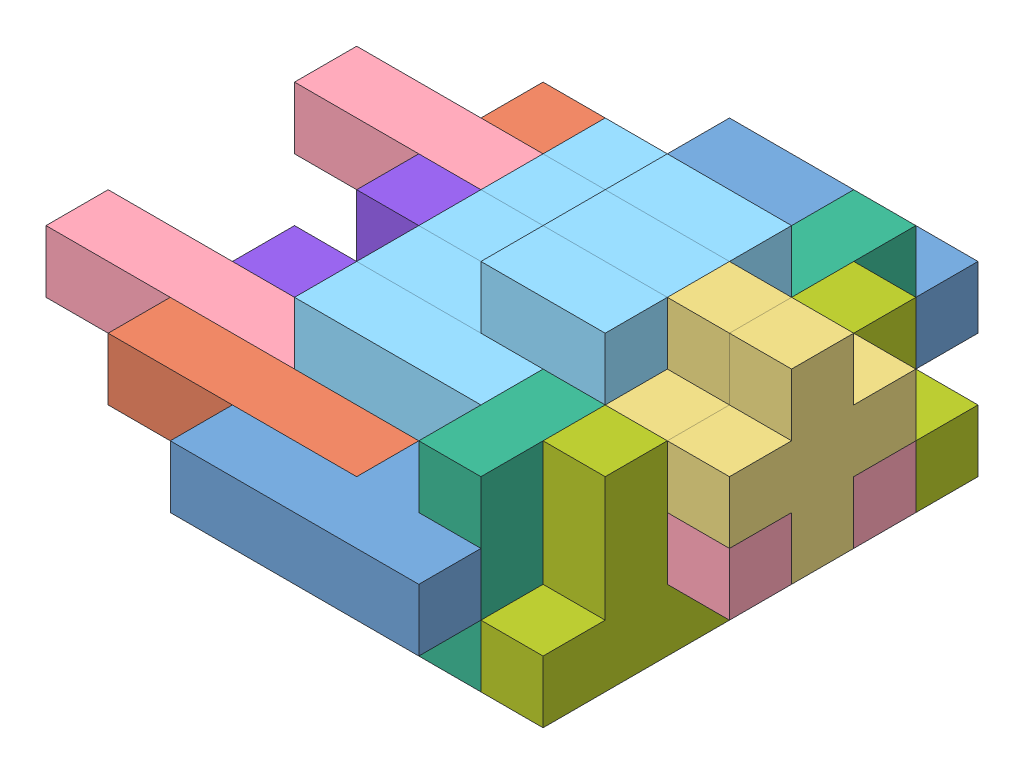
SolidWorks assembly Assem1, configuration Default. Lengths in mm.
Overall size (254 101.6 228.6).
23 component instances, 8 part files, 65 mates.
Components (placement in the parent):
- Block01-1: Block01 [Default] at (-218.9501 81.5478 299.8622) x (1 0 0) z (0 1 0) size (101.6 50.8 25.4)
- Block02-1: Block02 [Default] at (-168.1501 106.9478 274.4622) x (-1 0 0) z (0 -1 0) size (101.6 50.8 25.4)
- Block04-1: Block04 [Default] at (-117.3501 81.5478 223.6622) x (0 0 -1) z (1 0 0) size (76.2 76.2 25.4)
- Block05-1: Block05 [Default] at (-320.5501 81.5478 122.0622) size (127 25.4 25.4)
- Block06-1: Block06 [Default] at (-218.9501 81.5478 223.6622) size (101.6 50.8 25.4)
- Block07-1: Block07 [Default] at (-117.3501 132.3478 96.6622) x (0 -1 0) z (-1 0 0) size (76.2 76.2 25.4)
- Block08-1: Block08 [Default] at (-218.9501 106.9478 223.6622) x (0 0 -1) z (0 -1 0) size (76.2 76.2 25.4)
- Block11-1: Block11 [Default] at (-218.9501 106.9478 147.4622) x (0 0 1) z (0 -1 0) size (76.2 50.8 25.4)
- Block05-2: Block05 [Default] at (-320.5501 81.5478 223.6622) size (127 25.4 25.4)
- Block02-2: Block02 [Default] at (-168.1501 81.5478 96.6622) x (-1 0 0) z (0 1 0) size (101.6 50.8 25.4)
- Block01-2: Block01 [Default] at (-218.9501 106.9478 71.2622) x (1 0 0) z (0 -1 0) size (101.6 50.8 25.4)
- Block06-3: Block06 [Default] at (-218.9501 81.5478 122.0622) size (101.6 50.8 25.4)
- Block06-4: Block06 [Default] at (-218.9501 157.7478 172.8622) x (1 0 0) z (0 0 -1) size (101.6 50.8 25.4)
- Block06-5: Block06 [Default] at (-218.9501 157.7478 223.6622) x (1 0 0) z (0 0 -1) size (101.6 50.8 25.4)
- Block06-6: Block06 [Default] at (-218.9501 157.7478 198.2622) x (1 0 0) z (0 0 -1) size (101.6 50.8 25.4)
- Block07-2: Block07 [Default] at (-117.3501 132.3478 274.4622) x (0 0 -1) z (-1 0 0) size (76.2 76.2 25.4)
- Block05-3: Block05 [Default] at (-193.5501 81.5478 198.2622) size (127 25.4 25.4)
- Block05-4: Block05 [Default] at (-193.5501 81.5478 147.4622) size (127 25.4 25.4)
- Block01-3: Block01 [Default] at (-218.9501 81.5478 223.6622) x (1 0 0) z (0 -1 0) size (101.6 50.8 25.4)
- Block01-4: Block01 [Default] at (-218.9501 56.1478 147.4622) x (1 0 0) z (0 1 0) size (101.6 50.8 25.4)
- Block04-3: Block04 [Default] at (-91.9501 81.5478 223.6622) x (0 0 -1) z (1 0 0) size (76.2 76.2 25.4)
- Block08-2: Block08 [Default] at (-117.3501 56.1478 274.4622) x (0 0 -1) z (1 0 0) size (76.2 76.2 25.4)
- Block08-4: Block08 [Default] at (-117.3501 56.1478 172.8622) x (0 0 -1) z (1 0 0) size (76.2 76.2 25.4)
Mates (geometry in assembly coordinates):
- Coincident1: coincident anti-aligned: plane of Block05-1 through (-320.5501 81.5478 147.4622) normal (0 0 1); plane of Block11-1 through (-269.7501 81.5478 147.4622) normal (0 0 -1)
- Coincident4: coincident aligned: plane of Block05-1 through (-320.5501 106.9478 147.4622) normal (0 1 0); plane of Block11-1 through (-218.9501 106.9478 147.4622) normal (0 1 0)
- Coincident7: coincident aligned: plane of Block05-1 through (-193.5501 106.9478 147.4622) normal (1 0 0); plane of Block08-1 through (-193.5501 81.5478 147.4622) normal (1 0 0)
- Coincident8: coincident aligned: plane of Block05-1 through (-193.5501 81.5478 147.4622) normal (0 -1 0); plane of Block08-1 through (-218.9501 81.5478 223.6622) normal (0 -1 0)
- Coincident9: coincident anti-aligned: plane of Block05-1 through (-320.5501 81.5478 147.4622) normal (0 0 1); plane of Block08-1 through (-218.9501 81.5478 147.4622) normal (0 0 -1)
- Coincident10: coincident anti-aligned: plane of Block08-1 through (-218.9501 81.5478 223.6622) normal (-1 0 0); plane of Block11-1 through (-218.9501 81.5478 147.4622) normal (1 0 0)
- Coincident11: coincident anti-aligned: plane of Block11-1 through (-218.9501 81.5478 223.6622) normal (0 0 1); plane of Block05-2 through (-320.5501 81.5478 223.6622) normal (0 0 -1)
- Coincident12: coincident aligned: plane of Block08-1 through (-193.5501 81.5478 198.2622) normal (1 0 0); plane of Block05-2 through (-193.5501 106.9478 249.0622) normal (1 0 0)
- Coincident13: coincident aligned: plane of Block08-1 through (-218.9501 81.5478 223.6622) normal (0 -1 0); plane of Block05-2 through (-193.5501 81.5478 249.0622) normal (0 -1 0)
- Coincident14: coincident anti-aligned: plane of Block02-1 through (-269.7501 81.5478 249.0622) normal (0 0 -1); plane of Block05-2 through (-320.5501 81.5478 249.0622) normal (0 0 1)
- Coincident15: coincident aligned: plane of Block02-1 through (-168.1501 106.9478 274.4622) normal (0 1 0); plane of Block05-2 through (-320.5501 106.9478 249.0622) normal (0 1 0)
- Coincident16: coincident anti-aligned: plane of Block02-1 through (-193.5501 81.5478 249.0622) normal (-1 0 0); plane of Block08-1 through (-193.5501 81.5478 198.2622) normal (1 0 0)
- Coincident17: coincident anti-aligned: plane of Block05-1 through (-320.5501 81.5478 122.0622) normal (0 0 -1); plane of Block02-2 through (-269.7501 106.9478 122.0622) normal (0 0 1)
- Coincident18: coincident aligned: plane of Block05-1 through (-320.5501 106.9478 147.4622) normal (0 1 0); plane of Block02-2 through (-168.1501 106.9478 96.6622) normal (0 1 0)
- Coincident19: coincident anti-aligned: plane of Block05-1 through (-193.5501 106.9478 147.4622) normal (1 0 0); plane of Block02-2 through (-193.5501 106.9478 122.0622) normal (-1 0 0)
- Coincident20: coincident anti-aligned: plane of Block01-1 through (-168.1501 106.9478 274.4622) normal (0 0 -1); plane of Block02-1 through (-168.1501 81.5478 274.4622) normal (0 0 1)
- Coincident21: coincident anti-aligned: plane of Block01-1 through (-168.1501 106.9478 249.0622) normal (-1 0 0); plane of Block02-1 through (-168.1501 81.5478 223.6622) normal (1 0 0)
- Coincident22: coincident aligned: plane of Block01-1 through (-218.9501 106.9478 299.8622) normal (0 1 0); plane of Block02-1 through (-168.1501 106.9478 274.4622) normal (0 1 0)
- Coincident24: coincident anti-aligned: plane of Block02-2 through (-168.1501 106.9478 96.6622) normal (0 0 -1); plane of Block01-2 through (-168.1501 81.5478 96.6622) normal (0 0 1)
- Coincident25: coincident aligned: plane of Block02-2 through (-168.1501 106.9478 96.6622) normal (0 1 0); plane of Block01-2 through (-218.9501 106.9478 71.2622) normal (0 1 0)
- Coincident26: coincident aligned: plane of Block01-1 through (-117.3501 106.9478 299.8622) normal (1 0 0); plane of Block01-2 through (-117.3501 81.5478 71.2622) normal (1 0 0)
- Coincident27: coincident anti-aligned: plane of Block02-1 through (-168.1501 106.9478 274.4622) normal (0 1 0); plane of Block06-1 through (-218.9501 106.9478 249.0622) normal (0 -1 0)
- Coincident28: coincident aligned: plane of Block01-1 through (-117.3501 106.9478 299.8622) normal (1 0 0); plane of Block06-1 through (-117.3501 81.5478 249.0622) normal (1 0 0)
- Coincident29: coincident aligned: plane of Block06-1 through (-218.9501 81.5478 249.0622) normal (0 0 1); plane of Block05-2 through (-320.5501 81.5478 249.0622) normal (0 0 1)
- Coincident39: coincident aligned: plane of Block02-2 through (-193.5501 106.9478 147.4622) normal (0 0 1); plane of Block06-3 through (-218.9501 81.5478 147.4622) normal (0 0 1)
- Coincident40: coincident aligned: plane of Block06-1 through (-142.7501 132.3478 249.0622) normal (0 1 0); plane of Block06-3 through (-142.7501 132.3478 147.4622) normal (0 1 0)
- Coincident41: coincident aligned: plane of Block06-1 through (-218.9501 132.3478 249.0622) normal (-1 0 0); plane of Block06-3 through (-218.9501 132.3478 147.4622) normal (-1 0 0)
- Coincident42: coincident anti-aligned: plane of Block08-1 through (-218.9501 106.9478 223.6622) normal (0 1 0); plane of Block06-4 through (-142.7501 106.9478 147.4622) normal (0 -1 0)
- Coincident43: coincident aligned: plane of Block06-3 through (-218.9501 132.3478 147.4622) normal (-1 0 0); plane of Block06-4 through (-218.9501 106.9478 147.4622) normal (-1 0 0)
- Coincident44: coincident anti-aligned: plane of Block06-3 through (-218.9501 81.5478 147.4622) normal (0 0 1); plane of Block06-4 through (-218.9501 157.7478 147.4622) normal (0 0 -1)
- Coincident45: coincident aligned: plane of Block06-4 through (-168.1501 132.3478 147.4622) normal (-1 0 0); plane of Block06-5 through (-168.1501 132.3478 198.2622) normal (-1 0 0)
- Coincident46: coincident anti-aligned: plane of Block06-1 through (-218.9501 81.5478 223.6622) normal (0 0 -1); plane of Block06-5 through (-218.9501 157.7478 223.6622) normal (0 0 1)
- Coincident47: coincident aligned: plane of Block06-4 through (-168.1501 157.7478 147.4622) normal (0 1 0); plane of Block06-5 through (-168.1501 157.7478 198.2622) normal (0 1 0)
- Coincident49: coincident aligned: plane of Block06-4 through (-168.1501 157.7478 147.4622) normal (0 1 0); plane of Block06-6 through (-168.1501 157.7478 172.8622) normal (0 1 0)
- Coincident51: coincident aligned: plane of Block06-5 through (-168.1501 132.3478 198.2622) normal (-1 0 0); plane of Block06-6 through (-168.1501 132.3478 172.8622) normal (-1 0 0)
- Coincident56: coincident anti-aligned: plane of Block06-1 through (-117.3501 106.9478 249.0622) normal (0 1 0); plane of Block07-2 through (-142.7501 106.9478 198.2622) normal (0 -1 0)
- Coincident57: coincident anti-aligned: plane of Block01-1 through (-117.3501 106.9478 274.4622) normal (0 0 -1); plane of Block07-2 through (-142.7501 56.1478 274.4622) normal (0 0 1)
- Coincident58: coincident aligned: plane of Block01-1 through (-117.3501 106.9478 299.8622) normal (1 0 0); plane of Block07-2 through (-117.3501 132.3478 274.4622) normal (1 0 0)
- Coincident59: coincident aligned: plane of Block07-1 through (-117.3501 132.3478 96.6622) normal (1 0 0); plane of Block01-2 through (-117.3501 81.5478 71.2622) normal (1 0 0)
- Coincident60: coincident anti-aligned: plane of Block07-1 through (-142.7501 132.3478 96.6622) normal (0 0 -1); plane of Block01-2 through (-117.3501 81.5478 96.6622) normal (0 0 1)
- Coincident61: coincident aligned: plane of Block07-1 through (-142.7501 132.3478 172.8622) normal (0 1 0); plane of Block07-2 through (-142.7501 132.3478 274.4622) normal (0 1 0)
- Coincident62: coincident aligned: plane of Block05-2 through (-193.5501 81.5478 249.0622) normal (0 -1 0); plane of Block05-3 through (-66.5501 81.5478 223.6622) normal (0 -1 0)
- Coincident63: coincident anti-aligned: plane of Block08-1 through (-193.5501 81.5478 198.2622) normal (1 0 0); plane of Block05-3 through (-193.5501 81.5478 223.6622) normal (-1 0 0)
- Coincident64: coincident anti-aligned: plane of Block08-1 through (-142.7501 81.5478 198.2622) normal (0 0 1); plane of Block05-3 through (-193.5501 81.5478 198.2622) normal (0 0 -1)
- Coincident65: coincident aligned: plane of Block05-3 through (-66.5501 106.9478 223.6622) normal (1 0 0); plane of Block05-4 through (-66.5501 106.9478 172.8622) normal (1 0 0)
- Coincident66: coincident aligned: plane of Block02-2 through (-168.1501 81.5478 96.6622) normal (0 -1 0); plane of Block05-4 through (-66.5501 81.5478 172.8622) normal (0 -1 0)
- Coincident67: coincident anti-aligned: plane of Block08-1 through (-193.5501 81.5478 172.8622) normal (0 0 -1); plane of Block05-4 through (-193.5501 81.5478 172.8622) normal (0 0 1)
- Coincident68: coincident aligned: plane of Block07-2 through (-142.7501 56.1478 274.4622) normal (0 0 1); plane of Block01-3 through (-142.7501 56.1478 274.4622) normal (0 0 1)
- Coincident69: coincident aligned: plane of Block07-2 through (-142.7501 56.1478 249.0622) normal (0 -1 0); plane of Block01-3 through (-218.9501 56.1478 223.6622) normal (0 -1 0)
- Coincident70: coincident anti-aligned: plane of Block07-2 through (-142.7501 132.3478 274.4622) normal (-1 0 0); plane of Block01-3 through (-142.7501 56.1478 249.0622) normal (1 0 0)
- Coincident71: coincident anti-aligned: plane of Block07-1 through (-142.7501 132.3478 96.6622) normal (-1 0 0); plane of Block01-4 through (-142.7501 81.5478 122.0622) normal (1 0 0)
- Coincident72: coincident anti-aligned: plane of Block02-2 through (-168.1501 81.5478 96.6622) normal (0 -1 0); plane of Block01-4 through (-218.9501 81.5478 147.4622) normal (0 1 0)
- Coincident73: coincident anti-aligned: plane of Block07-1 through (-142.7501 56.1478 122.0622) normal (0 0 1); plane of Block01-4 through (-168.1501 81.5478 122.0622) normal (0 0 -1)
- Coincident74: coincident anti-aligned: plane of Block04-1 through (-117.3501 81.5478 223.6622) normal (-1 0 0); plane of Block07-1 through (-117.3501 132.3478 96.6622) normal (1 0 0)
- Coincident75: coincident anti-aligned: plane of Block04-1 through (-91.9501 106.9478 198.2622) normal (0 -1 0); plane of Block05-3 through (-193.5501 106.9478 223.6622) normal (0 1 0)
- Coincident76: coincident aligned: plane of Block04-1 through (-91.9501 106.9478 223.6622) normal (0 0 1); plane of Block05-3 through (-193.5501 81.5478 223.6622) normal (0 0 1)
- Coincident77: coincident anti-aligned: plane of Block04-1 through (-91.9501 81.5478 223.6622) normal (1 0 0); plane of Block04-3 through (-91.9501 81.5478 223.6622) normal (-1 0 0)
- Coincident78: coincident aligned: plane of Block04-1 through (-91.9501 157.7478 198.2622) normal (0 1 0); plane of Block04-3 through (-66.5501 157.7478 198.2622) normal (0 1 0)
- Coincident79: coincident aligned: plane of Block04-1 through (-91.9501 106.9478 223.6622) normal (0 0 1); plane of Block04-3 through (-66.5501 106.9478 223.6622) normal (0 0 1)
- Coincident80: coincident anti-aligned: plane of Block05-3 through (-193.5501 81.5478 223.6622) normal (0 0 1); plane of Block08-2 through (-91.9501 81.5478 223.6622) normal (0 0 -1)
- Coincident81: coincident anti-aligned: plane of Block07-2 through (-117.3501 132.3478 274.4622) normal (1 0 0); plane of Block08-2 through (-117.3501 56.1478 274.4622) normal (-1 0 0)
- Coincident82: coincident aligned: plane of Block01-3 through (-218.9501 56.1478 223.6622) normal (0 -1 0); plane of Block08-2 through (-91.9501 56.1478 274.4622) normal (0 -1 0)
- Coincident86: coincident anti-aligned: plane of Block04-1 through (-91.9501 132.3478 147.4622) normal (0 0 -1); plane of Block08-4 through (-91.9501 132.3478 147.4622) normal (0 0 1)
- Coincident87: coincident aligned: plane of Block08-2 through (-91.9501 132.3478 223.6622) normal (0 1 0); plane of Block08-4 through (-91.9501 132.3478 122.0622) normal (0 1 0)
- Coincident88: coincident aligned: plane of Block08-2 through (-91.9501 56.1478 274.4622) normal (1 0 0); plane of Block08-4 through (-91.9501 56.1478 172.8622) normal (1 0 0)
